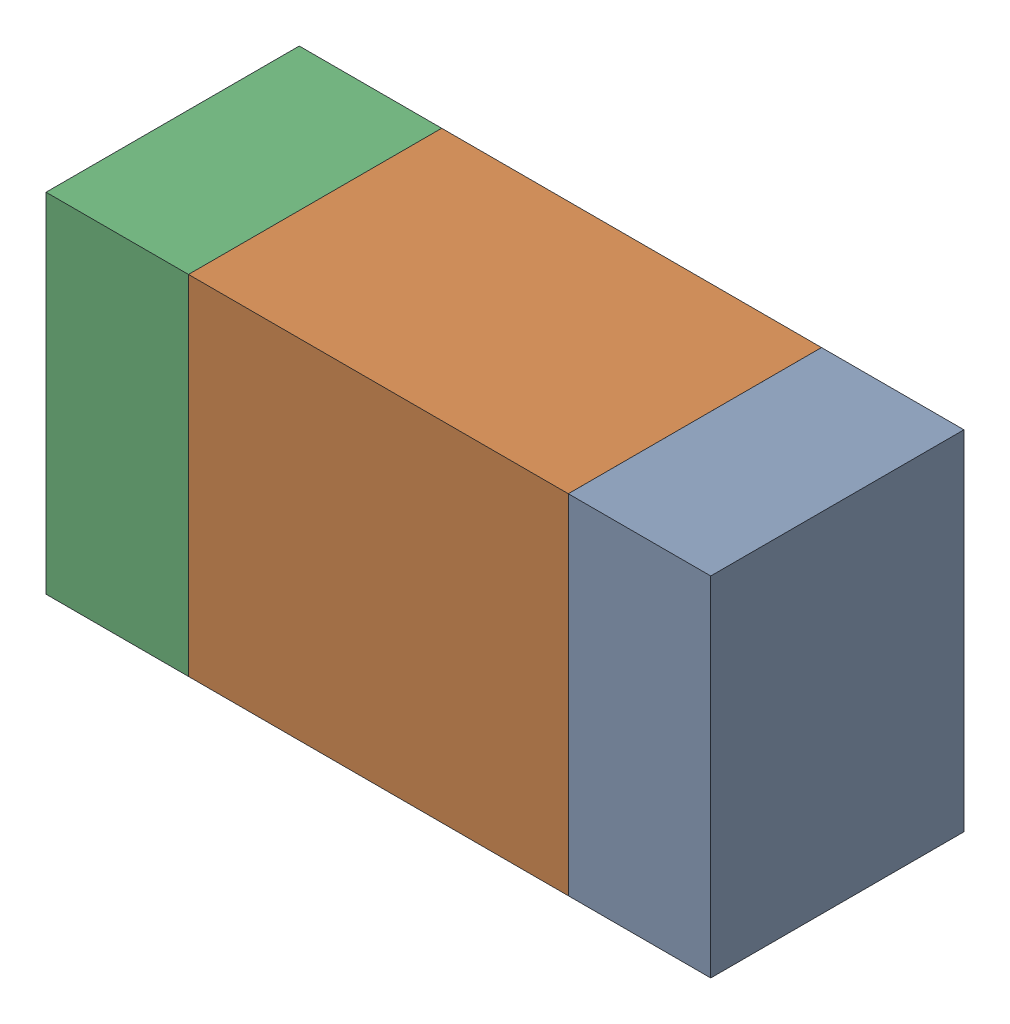
SolidWorks assembly R302_1PCB, configuration Default. Lengths in mm.
Overall size (1.05 0.55 0.4).
6 component instances, 2 part files, 0 mates.
Components (placement in the parent):
- 854785432-1: 854785432 [Default] at (140.6126 113.7001 0) size (0.22 0.55 0.4)
  - Extruded-1: Extruded [Default] at origin size (0.22 0.55 0.4)
- 854785568-1: 854785568 [Default] at (140.2001 113.7001 0) size (0.6 0.55 0.4)
  - Extruded_2-1: Extruded_2 [Default] at origin size (0.6 0.55 0.4)
- 854785432-2: 854785432 [Default] at (139.7876 113.7001 0) size (0.22 0.55 0.4)
  - Extruded-1: Extruded [Default] at origin size (0.22 0.55 0.4)
